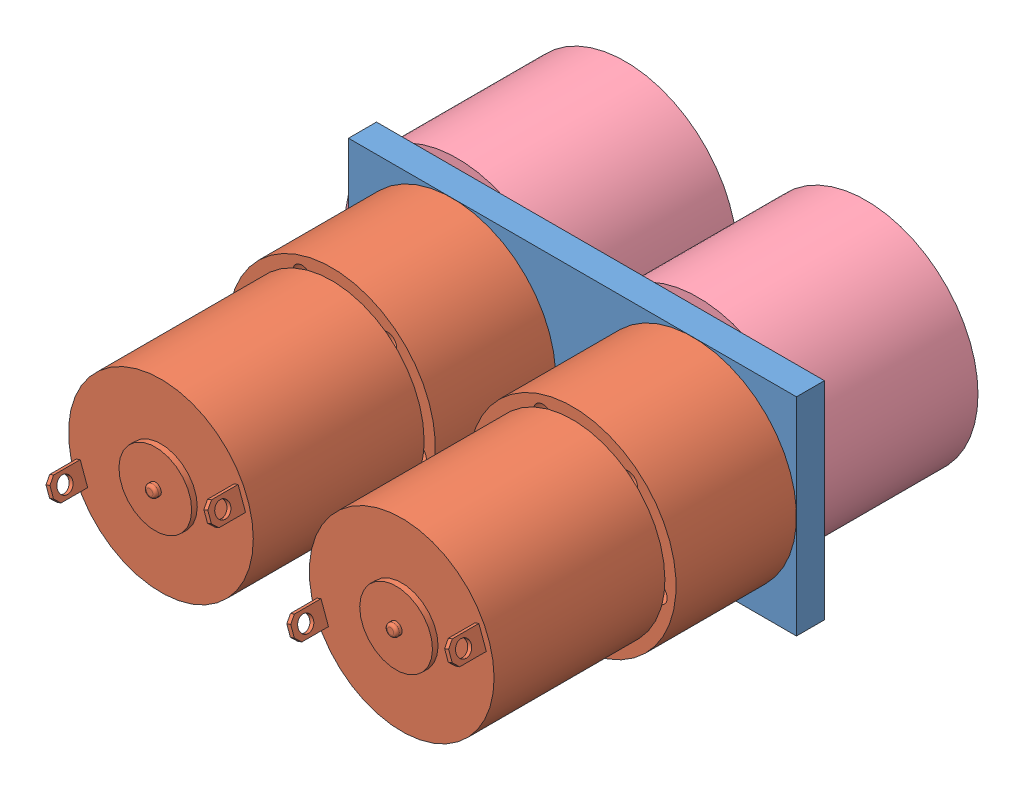
SolidWorks assembly Ruedas_I, configuration Predeterminado. Lengths in mm.
Overall size (88.08 44.6 128.99).
17 component instances, 4 part files, 20 mates.
Components (placement in the parent):
- Bracket_Motor_I-1: Bracket_Motor_I [Predeterminado] at (-18.8779 -3.7105 77.5) size (85 37 5)
- Titan-37mm-500rpm-3: Titan-37mm-500rpm [Predeterminado] at (2.6242 -3.7097 104) x (-0.34202 0.939693 0) z (0 0 -1) size (37 37 78.75)
- Titan-37mm-500rpm-4: Titan-37mm-500rpm [Predeterminado] at (-40.3758 -3.7097 104) x (-0.34202 0.939693 0) z (0 0 -1) size (37 37 78.75)
- Tornillo M3x15-1: Tornillo M3x15 [Predeterminado] at (-45.6792 10.8547 92.5) x (-1 0 0) z (0 0 -1) size (5 5 15.24)
- Tornillo M3x15-2: Tornillo M3x15 [Predeterminado] at (-30.4147 8.1632 92.5) x (-1 0 0) z (0 0 -1) size (5 5 15.24)
- Tornillo M3x15-3: Tornillo M3x15 [Predeterminado] at (-25.1134 -6.402 92.5) x (-1 0 0) z (0 0 -1) size (5 5 15.24)
- Tornillo M3x15-4: Tornillo M3x15 [Predeterminado] at (-35.0766 -18.2757 92.5) x (-1 0 0) z (0 0 -1) size (5 5 15.24)
- Tornillo M3x15-5: Tornillo M3x15 [Predeterminado] at (-50.3411 -15.5842 92.5) x (-1 0 0) z (0 0 -1) size (5 5 15.24)
- Tornillo M3x15-6: Tornillo M3x15 [Predeterminado] at (17.8866 -6.402 92.5) x (-1 0 0) z (0 0 -1) size (5 5 15.24)
- Tornillo M3x15-7: Tornillo M3x15 [Predeterminado] at (-7.3411 -15.5842 92.5) x (-1 0 0) z (0 0 -1) size (5 5 15.24)
- Tornillo M3x15-8: Tornillo M3x15 [Predeterminado] at (-12.6424 -1.0189 92.5) x (-1 0 0) z (0 0 -1) size (5 5 15.24)
- Tornillo M3x15-9: Tornillo M3x15 [Predeterminado] at (-55.6424 -1.0189 92.5) x (-1 0 0) z (0 0 -1) size (5 5 15.24)
- Tornillo M3x15-10: Tornillo M3x15 [Predeterminado] at (12.5853 8.1632 92.5) x (-1 0 0) z (0 0 -1) size (5 5 15.24)
- Tornillo M3x15-11: Tornillo M3x15 [Predeterminado] at (7.9234 -18.2757 92.5) x (-1 0 0) z (0 0 -1) size (5 5 15.24)
- Tornillo M3x15-12: Tornillo M3x15 [Predeterminado] at (-2.6792 10.8547 92.5) x (-1 0 0) z (0 0 -1) size (5 5 15.24)
- js4030-wheel-cad-1: js4030-wheel-cad [Predeterminado] at (16.2907 -5.5589 20) size (40 40 30)
- js4030-wheel-cad-2: js4030-wheel-cad [Predeterminado] at (-26.7093 -5.5589 20) size (40 40 30)
Mates (geometry in assembly coordinates):
- Coincidente2: coincident anti-aligned: plane of Bracket_Motor_I-1 through (-18.8779 -3.7105 82.5) normal (0 0 1); plane of Titan-37mm-500rpm-4 through (-40.3758 -3.7097 82.5) normal (0 0 -1)
- Coincidente3: coincident anti-aligned: plane of Bracket_Motor_I-1 through (-18.8779 -3.7105 82.5) normal (0 0 1); plane of Titan-37mm-500rpm-3 through (2.6242 -3.7097 82.5) normal (0 0 -1)
- Concéntrica3: concentric anti-aligned: cylinder of Bracket_Motor_I-1 through (-3.9558 -6.1046 77.5) axis (0 0 1) radius 6; cylinder of Titan-37mm-500rpm-3 through (-3.9558 -6.1046 82.5) axis (0 0 -1) radius 6
- Concéntrica4: concentric anti-aligned: cylinder of Bracket_Motor_I-1 through (-46.9558 -6.1046 77.5) axis (0 0 1) radius 6; cylinder of Titan-37mm-500rpm-4 through (-46.9558 -6.1046 82.5) axis (0 0 -1) radius 6
- Coincidente4: coincident aligned: cone of Bracket_Motor_I-1 through (7.9234 -18.2757 79.5) axis (0 0 1); cone of Tornillo M3x15-11 through (7.9234 -18.2757 78) axis (0 0 1)
- Coincidente5: coincident aligned: cone of Bracket_Motor_I-1 through (17.8866 -6.402 79.5) axis (0 0 1); cone of Tornillo M3x15-6 through (17.8866 -6.402 78) axis (0 0 1)
- Coincidente6: coincident aligned: cone of Bracket_Motor_I-1 through (12.5853 8.1632 79.5) axis (0 0 1); cone of Tornillo M3x15-10 through (12.5853 8.1632 78) axis (0 0 1)
- Coincidente7: coincident aligned: cone of Bracket_Motor_I-1 through (-7.3411 -15.5842 79.5) axis (0 0 1); cone of Tornillo M3x15-7 through (-7.3411 -15.5842 78) axis (0 0 1)
- Coincidente8: coincident aligned: cone of Bracket_Motor_I-1 through (-2.6792 10.8547 79.5) axis (0 0 1); cone of Tornillo M3x15-12 through (-2.6792 10.8547 78) axis (0 0 1)
- Coincidente9: coincident aligned: cone of Bracket_Motor_I-1 through (-12.6424 -1.0189 79.5) axis (0 0 1); cone of Tornillo M3x15-8 through (-12.6424 -1.0189 78) axis (0 0 1)
- Coincidente10: coincident aligned: cone of Bracket_Motor_I-1 through (-25.1134 -6.402 79.5) axis (0 0 1); cone of Tornillo M3x15-3 through (-25.1134 -6.402 78) axis (0 0 1)
- Coincidente11: coincident aligned: cone of Bracket_Motor_I-1 through (-30.4147 8.1632 79.5) axis (0 0 1); cone of Tornillo M3x15-2 through (-30.4147 8.1632 78) axis (0 0 1)
- Coincidente12: coincident aligned: cone of Bracket_Motor_I-1 through (-35.0766 -18.2757 79.5) axis (0 0 1); cone of Tornillo M3x15-4 through (-35.0766 -18.2757 78) axis (0 0 1)
- Coincidente13: coincident aligned: cone of Bracket_Motor_I-1 through (-50.3411 -15.5842 79.5) axis (0 0 1); cone of Tornillo M3x15-5 through (-50.3411 -15.5842 78) axis (0 0 1)
- Coincidente14: coincident aligned: cone of Bracket_Motor_I-1 through (-45.6792 10.8547 79.5) axis (0 0 1); cone of Tornillo M3x15-1 through (-45.6792 10.8547 78) axis (0 0 1)
- Coincidente15: coincident aligned: cone of Bracket_Motor_I-1 through (-55.6424 -1.0189 79.5) axis (0 0 1); cone of Tornillo M3x15-9 through (-55.6424 -1.0189 78) axis (0 0 1)
- Distancia1: distance = 1.5 mm aligned: plane of js4030-wheel-cad-2 through (-46.9558 -6.1046 75) normal (0 0 -1); plane of Titan-37mm-500rpm-4 through (-46.9558 -6.1046 76.5) normal (0 0 -1)
- Coincidente17: coincident aligned: plane of js4030-wheel-cad-1 through (-3.9558 -6.1046 75) normal (0 0 1); plane of js4030-wheel-cad-2 through (-46.9558 -6.1046 75) normal (0 0 1)
- Concéntrica5: concentric aligned: cylinder of Titan-37mm-500rpm-4 through (-46.9558 -6.1046 76.5) axis (0 0 -1) radius 3; cylinder of js4030-wheel-cad-2 through (-46.9558 -6.1046 75) axis (0 0 -1) radius 3
- Concéntrica6: concentric aligned: cylinder of Titan-37mm-500rpm-3 through (-3.9558 -6.1046 76.5) axis (0 0 -1) radius 3; cylinder of js4030-wheel-cad-1 through (-3.9558 -6.1046 75) axis (0 0 -1) radius 3
